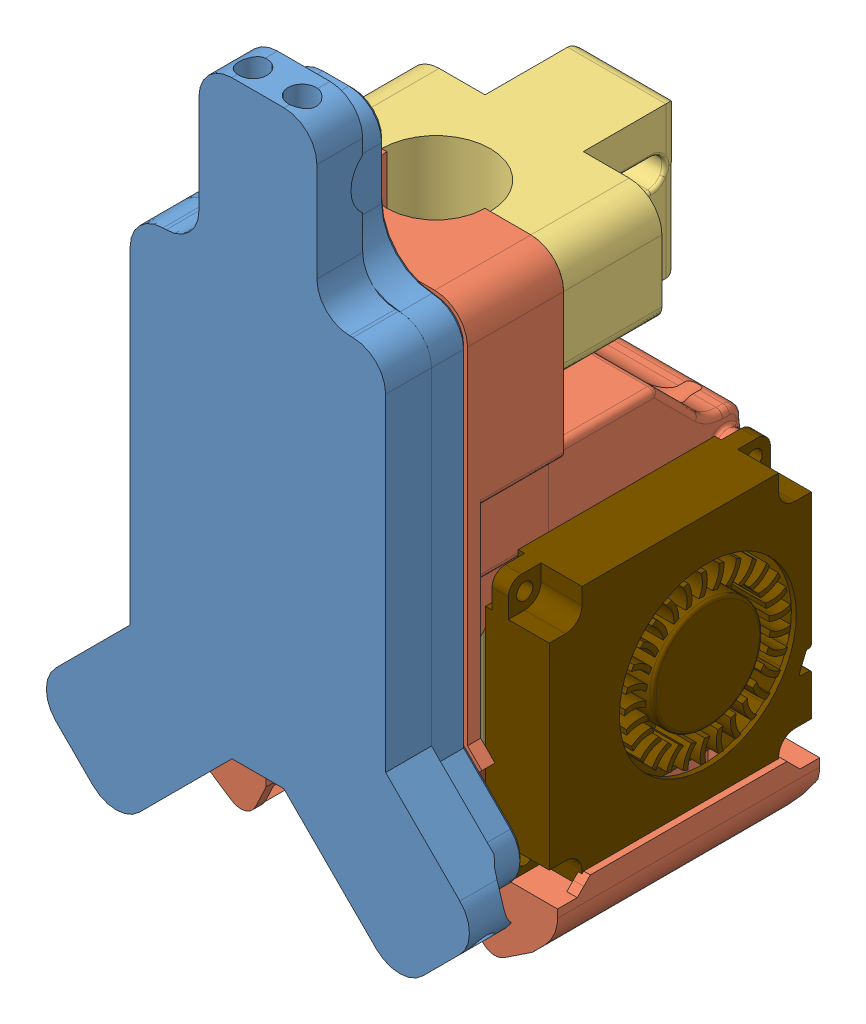
SolidWorks assembly v6_tool_good, configuration Default. Lengths in mm.
Overall size (57.93 110.7 55.76).
34 component instances, 21 part files, 24 mates.
Components (placement in the parent):
- tool_changer_tool-1: tool_changer_tool [Default] at (22.7828 49.8667 93.4265) size (64.58 105.62 12.5)
- Fans_mount-1: Fans_mount [Default] at (20.6112 5.5043 80.6566) x (-1 0 0) z (0 1 0) size (57.93 44.3 87.63)
- e3D V6 1.75mm Hotend Assembly Mockup-1: e3D V6 1.75mm Hotend Assembly Mockup [Default] at (22.7949 9.4443 72.3301) x (0.170129 0 0.985422) z (0 1 0) size (38.97 30.07 64.5)
  - e3D V6 1.75mm Hotend Assembly Mockup.step-1: e3D V6 1.75mm Hotend Assembly Mockup.step [Default] at origin size (38.97 30.07 64.5)
    - V6-175-SINK.step-1: V6-175-SINK.step [Default] at (-0.0711 0 18.6) x (1 0.000031 0) z (0 0 1) size (22.3 22.3 44.95)
      - PTFE Tube Retainer.step-1: PTFE Tube Retainer.step [Default] at (0 0 1) x (-0.000024 -1 0) z (0 0 1) size (8 9 6.78)
        - Collet.step-1: Collet.step [Default] at (0 0 43.9) x (0 1 0) z (0 0 1) size (7 7 6.78)
        - Coupling.step-1: Coupling.step [Default] at (0 0 41.7) x (-0.000024 1 0) z (0 0 1) size (8 8 3.48)
        - Collet Clip.step-1: Collet Clip.step [Default] at (0 0 41.7) size (8 8.46 2)
      - V6-175-SINK-0.step-1: V6-175-SINK-0.step [Default] at origin size (22.3 22.3 42.75)
    - V6-Heatblock.step-1: V6-Heatblock.step [Default] at (-0.071 0.0711 5) x (1 0.000009 0) z (0 0 1) size (24.2 21 13.2)
      - M3x10 rounded head screw - 92095A182 (1).step-1: M3x10 rounded head screw - 92095A182 (1).step [Default] at (-12.5025 0 -1.6476) x (0.335243 0.942132 0) z (0 0 -1) size (5.7 5.7 11.65)
      - M3x4 flat tip set screw - 92605A098.step-1: M3x4 flat tip set screw - 92605A098.step [Default] at (6.0115 0 2.0029) x (-1 0.000002 0) z (0 0 -1) size (4.15 4.13 4)
      - Thermistor.step-1: Thermistor.step [Default] at (-0.0065 -2.7408 13.5951) x (1 0 0.000823) z (-0.000823 0 1) size (3 13.5 3)
      - Heater Cartridge.step-1: Heater Cartridge.step [Default] at (0.0988 0 0.1652) x (0.999682 0 0.025219) z (-0.025219 0 0.999682) size (5.9 21 5.9)
      - V6-Heatblock-1.step-1: V6-Heatblock-1.step [Default] at origin size (23 16 11.6)
    - Fan Assembly.step-1: Fan Assembly.step [Default] at (0 -26 15) size (33.65 30.07 30.1) (hidden)
      - Fan Shroud.step-1: Fan Shroud.step [Default] at (-16.2408 26 3.6) x (0 -1 0) z (0 0 1) size (30.07 22.05 30.1)
      - 30x10mm box fan.step-1: 30x10mm box fan.step [Default] at (-26.2408 26 18.6) x (0 -1 0) z (0 0 1) size (30 10 30)
      - M3x16 rounded head screw - 92095A184.step-1: M3x16 rounded head screw - 92095A184.step [Default] at (-27.8908 14 6.6) x (0 -1 0) z (-1 0 0) size (5.7 5.7 17.65)
      - M3x16 rounded head screw - 92095A184.step-2: M3x16 rounded head screw - 92095A184.step [Default] at (-27.8908 38 6.6) x (0 0 -1) z (-1 0 0) size (5.7 5.7 17.65)
      - M3x16 rounded head screw - 92095A184.step-3: M3x16 rounded head screw - 92095A184.step [Default] at (-27.8908 38 30.6) x (0 1 0) z (-1 0 0) size (5.7 5.7 17.65)
      - M3x16 rounded head screw - 92095A184.step-4: M3x16 rounded head screw - 92095A184.step [Default] at (-27.8908 14 30.6) x (0 0 1) z (-1 0 0) size (5.7 5.7 17.65)
    - V6-Heatbreak.step-1: V6-Heatbreak.step [Default] at (-0.071 0.0711 11.5) x (-1 -0.000034 0) z (0 0 1) size (6.99 6.98 22.15)
    - V6-175-Nozzle 0.4mm.step-1: V6-175-Nozzle 0.4mm.step [Default] at (-0.071 0.0711 1) x (1 0.000007 0) z (0 0 1) size (8.08 7 12.55)
- kinematic_ball-1: kinematic_ball [Default] at (22.7828 112.1417 93.0091) x (1 0 0) z (0 -1 0) size (10 9.58 10)
- kinematic_ball-2: kinematic_ball [Default] at (2.5374 29.6743 93.0091) x (1 0 0) z (0 -1 0) size (10 9.58 10)
- kinematic_ball-3: kinematic_ball [Default] at (43.0547 29.7009 93.0091) x (1 0 0) z (0 -1 0) size (10 9.58 10)
- 4010 - Blower Assembly-1: 4010 - Blower Assembly [Default] at (25.7018 13.7492 84.4979) x (0 0 -1) z (1 0 0) size (40 40 9.75)
- 4010 - Blower Assembly-2: 4010 - Blower Assembly [Default] at (19.8793 13.7492 41.3211) x (0 0 1) z (-1 0 0) size (40 40 9.75)
- Fan 3010-1: Fan 3010 [Default] at (-49.6773 81.3366 50.2549) x (-1 0 0) z (0 -1 0) size (38.06 10.51 38.06)
  - Fan Casca-1: Fan Casca [Default] at (-72.4601 -2.5046 36.5408) size (30 10 30)
  - Fan Helices-1: Fan Helices [Default] at (-72.4601 -1.9046 36.5408) x (0.562267 0 -0.826955) z (0.826955 0 0.562267) size (27.4 10.25 27.4)
- tool_dock_tool-1: tool_dock_tool [Default] at (20.6112 5.5043 72.2601) x (1 0 0) z (0 0 -1) size (78 23.08 29.6)
Mates (geometry in assembly coordinates):
- Coincident2: coincident anti-aligned: plane of tool_changer_tool-1 through (22.7828 49.8667 86.9265) normal (0 0 -1); plane of Fans_mount-1 through (20.6112 5.5043 86.9265) normal (0 0 1)
- Concentric6: concentric aligned: cylinder of tool_changer_tool-1 through (34.3328 65.6334 80.8454) axis (0 0 1) radius 2.15; cylinder of Fans_mount-1 through (34.3328 65.6334 42.6595) axis (0 0 1) radius 1.75
- Concentric7: concentric aligned: cylinder of Fans_mount-1 through (22.7828 61.1443 72.2601) axis (0 1 0) radius 6.05; cylinder of e3D V6 1.75mm Hotend Assembly Mockup-1/e3D V6 1.75mm Hotend Assembly Mockup.step-1/V6-175-SINK.step-1/V6-175-SINK-0.step-1 through (22.7828 61.0443 72.2601) axis (0 1 0) radius 6
- Coincident3: coincident anti-aligned: plane of Fans_mount-1 through (22.7585 67.0443 76.1933) normal (0 1 0); plane of e3D V6 1.75mm Hotend Assembly Mockup-1/e3D V6 1.75mm Hotend Assembly Mockup.step-1/V6-175-SINK.step-1/V6-175-SINK-0.step-1 through (22.7828 67.0443 72.2601) normal (0 -1 0)
- Concentric9: concentric aligned: circle of tool_changer_tool-1; circle of kinematic_ball-1
- Coincident4: coincident anti-aligned: plane of tool_changer_tool-1 through (22.7828 112.1417 88.4265) normal (0 0 1); plane of kinematic_ball-1 through (22.7828 112.1417 88.4265) normal (0 0 -1)
- Concentric10: concentric aligned: circle of tool_changer_tool-1; circle of kinematic_ball-2
- Coincident5: coincident anti-aligned: plane of tool_changer_tool-1 through (22.7828 49.8667 88.4265) normal (0 0 1); circle of kinematic_ball-2
- Concentric11: concentric aligned: circle of tool_changer_tool-1; circle of kinematic_ball-3
- Coincident6: coincident anti-aligned: plane of tool_changer_tool-1 through (22.7828 49.8667 88.4265) normal (0 0 1); circle of kinematic_ball-3
- Coincident7: coincident aligned: plane of tool_changer_tool-1 through (42.2828 49.8667 86.9265) normal (1 0 0); plane of Fans_mount-1 through (42.2828 58.7468 84.9265) normal (1 0 0)
- Coincident8: coincident anti-aligned: plane of Fans_mount-1 through (41.9908 41.4088 62.6595) normal (1 0 0); plane of 4010 - Blower Assembly-1 through (41.9908 41.1545 62.9095) normal (-1 0 0)
- Concentric12: concentric aligned: circle of Fans_mount-1; circle of 4010 - Blower Assembly-1
- Parallel1: parallel aligned: plane of Fans_mount-1 through (22.7905 70.8334 61.4868) normal (0 1 0); plane of 4010 - Blower Assembly-1 through (50.9908 61.1545 62.9095) normal (0 1 0)
- Concentric13: concentric anti-aligned: cylinder of Fans_mount-1 through (6.5903 58.6545 45.4095) axis (-1 0 0) radius 2; cylinder of 4010 - Blower Assembly-2 through (1.0903 58.6545 45.4095) axis (1 0 0) radius 1.25
- Coincident10: coincident anti-aligned: plane of Fans_mount-1 through (3.5903 41.4088 62.6595) normal (-1 0 0); plane of 4010 - Blower Assembly-2 through (3.5903 41.1545 62.9095) normal (1 0 0)
- Parallel2: parallel aligned: plane of Fans_mount-1 through (22.7905 70.8334 61.4868) normal (0 1 0); plane of 4010 - Blower Assembly-2 through (-5.4097 61.1545 62.9095) normal (0 1 0)
- Width1: width anti-aligned: plane of Fan 3010-1/Fan Casca-1 through (7.7828 56.7958 42.7595) normal (-1 0 0); plane of Fan 3010-1/Fan Casca-1 through (37.7828 56.7958 42.7595) normal (1 0 0); plane of Fans_mount-1 through (7.6828 25.325 43.351) normal (1 0 0); plane of Fans_mount-1 through (37.8828 31.3943 42.6595) normal (-1 0 0)
- Width2: width anti-aligned: plane of Fan 3010-1/Fan Casca-1 through (34.7828 59.7958 42.7595) normal (0 1 0); plane of Fan 3010-1/Fan Casca-1 through (34.7828 29.7958 42.7595) normal (0 -1 0); plane of Fans_mount-1 through (37.5955 59.8472 42.6595) normal (0 -1 0); plane of Fans_mount-1 through (35.9955 29.7443 43.351) normal (0 1 0)
- Coincident12: coincident anti-aligned: plane of Fans_mount-1 through (22.7905 40.0319 52.7595) normal (0 0 -1); plane of Fan 3010-1/Fan Casca-1 through (10.7828 56.7958 52.7595) normal (0 0 1)
- InPlace1: in place: plane of Fans_mount-1 through (4.7828 73.6334 72.2601) normal (0 0 -1); plane of ? through (0 0 72.2601) normal (0 0 -1); moOrthogonalPlaneRef_w of Fans_mount-1 through (4.7828 73.6334 72.2601) normal (0 0 -1); plane of ? through (0 0 72.2601) normal (0 1 0); plane of Fans_mount-1 through (4.7828 73.6334 72.2601) normal (0 0 -1); plane of ? through (0 0 72.2601) normal (-1 0 0); plane of Fans_mount-1 through (4.7828 73.6334 72.2601) normal (0 0 -1); unknown of tool_dock_tool-1
- Coincident13: coincident aligned: plane of Fans_mount-1; plane of tool_dock_tool-1
- Coincident14: coincident aligned: moOrthogonalPlaneRef_w of Fans_mount-1 through (20.6112 5.5043 72.2601) normal (0 -1 0); plane of tool_dock_tool-1 through (20.6112 5.5043 72.2601) normal (0 -1 0)
- Coincident15: coincident anti-aligned: moOrthogonalPlaneRef_w of Fans_mount-1 through (20.6112 5.5043 72.2601) normal (-1 0 0); plane of tool_dock_tool-1 through (20.6112 5.5043 72.2601) normal (1 0 0)
